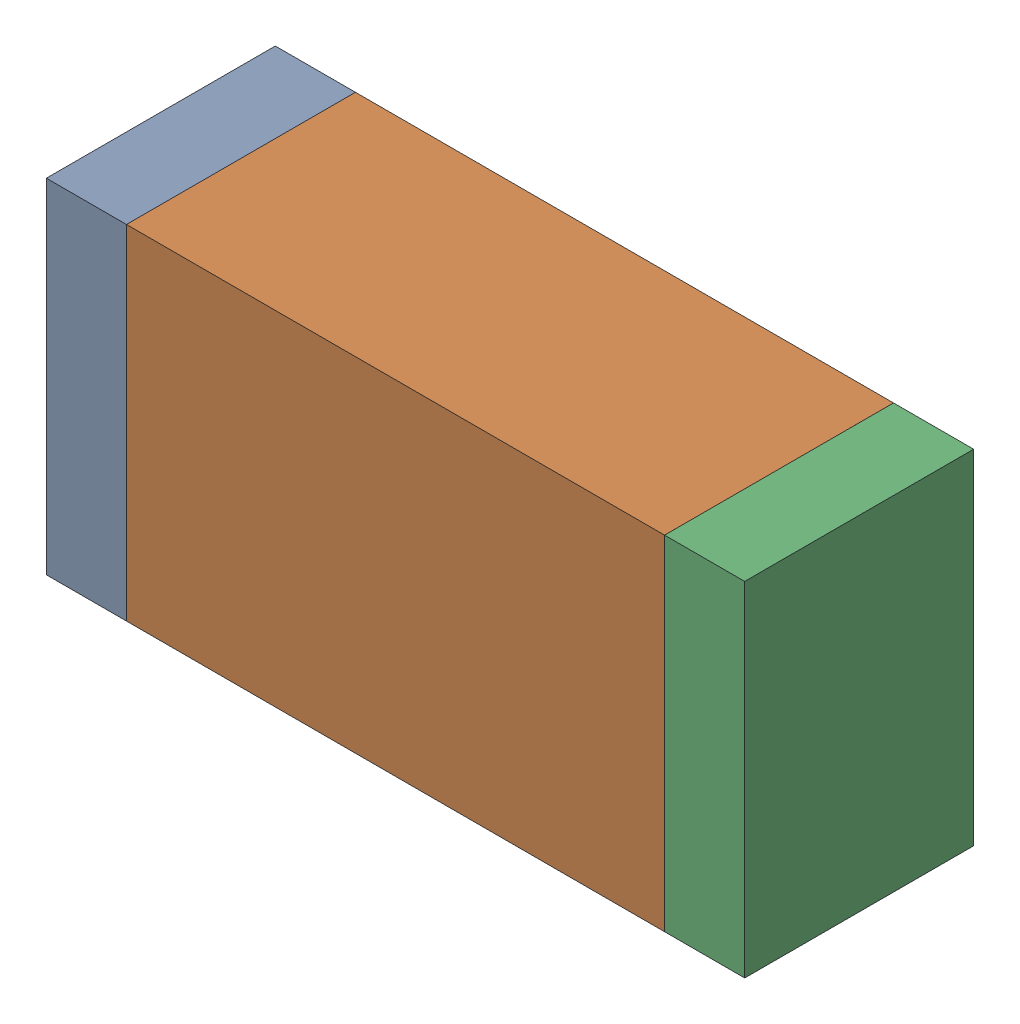
SolidWorks assembly R12, configuration Default. Lengths in mm.
Overall size (1.55 0.76 0.51).
6 component instances, 2 part files, 0 mates.
Components (placement in the parent):
- 822490216-1: 822490216 [Default] at (21.4375 1.7525 0) size (0.18 0.76 0.51)
  - Extruded-1: Extruded [Default] at origin size (0.18 0.76 0.51)
- 822498920-1: 822498920 [Default] at (22.1233 1.7525 0) size (1.19 0.76 0.51)
  - Extruded_2-1: Extruded_2 [Default] at origin size (1.19 0.76 0.51)
- 822490216-2: 822490216 [Default] at (22.8091 1.7525 0) size (0.18 0.76 0.51)
  - Extruded-1: Extruded [Default] at origin size (0.18 0.76 0.51)
